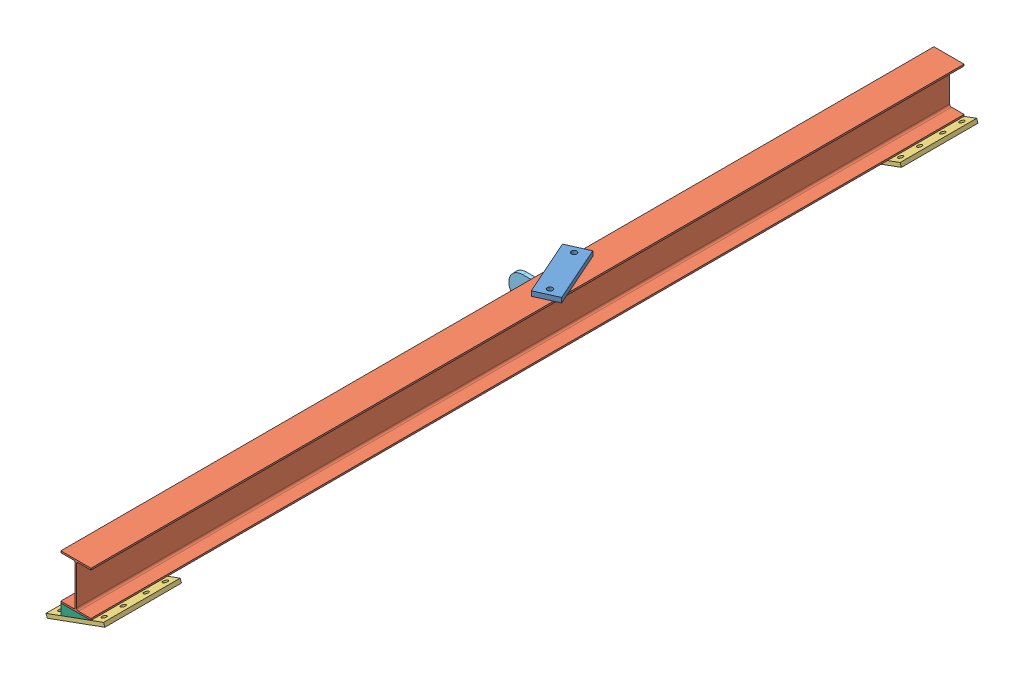
SolidWorks assembly _2014-10-29 WELMENT, STBD BOOM BASE, configuration Default. Lengths in mm.
Overall size (247.79 231.96 2895.6).
12 component instances, 7 part files, 24 mates.
Components (placement in the parent):
- PLATE, PILLOW BLOCK MOUNTING, BASE 1,2-1: PLATE, PILLOW BLOCK MOUNTING, BASE 1,2 [Default] at (-7.2804 74.93 -171.8129) x (0 1 0) z (-0.406737 0 -0.913545) size (15.88 76.2 203.2)
- BEAM, BASE 1-1: BEAM, BASE 1 [Default] at origin size (100.08 149.86 2895.6)
- PLATE, PLATFORM MOUNTING, BASE 1,2-1: PLATE, PLATFORM MOUNTING, BASE 1,2 [Default] at (-3.6654 -94.4765 -1320.8) x (0.34202 -0.939693 0) z (0 0 1) size (12.7 203.2 254)
- PLATE, PLATFORM MOUNTING, BASE 1,2-2: PLATE, PLATFORM MOUNTING, BASE 1,2 [Default] at (-3.6654 -94.4765 1320.8) x (0.34202 -0.939693 0) z (0 0 1) size (12.7 203.2 254)
- PLATE, BEAM REINFORCEMENT, BASE 1-1: PLATE, BEAM REINFORCEMENT, BASE 1 [Default] at (-46.863 0 0) size (6.35 138.94 1816.1)
- PADEYE, BEAM, BASE 1-1: PADEYE, BEAM, BASE 1 [Default] at (-50.038 0 -146.05) x (0 -0.069756 0.997564) z (0 -0.997564 -0.069756) size (12.7 101.6 101.6)
- FILLER PLATE 1-1: FILLER PLATE 1 [Default] at (50.038 -74.93 -1435.1) x (-1 0 0) z (0 -1 0) size (100.08 12.7 36.42)
- FILLER PLATE 1-2: FILLER PLATE 1 [Default] at (50.038 -74.93 -1193.8) x (-1 0 0) z (0 -1 0) size (100.08 12.7 36.42)
- FILLER PLATE 2-1: FILLER PLATE 2 [Default] at (-33.3992 -74.93 -1435.1) x (-1 0 0) z (0 0 -1) size (16.64 36.42 228.6)
- FILLER PLATE 2-2: FILLER PLATE 2 [Default] at (-33.3992 -74.93 1206.5) x (-1 0 0) z (0 0 -1) size (16.64 36.42 228.6)
- FILLER PLATE 1-3: FILLER PLATE 1 [Default] at (50.038 -74.93 1206.5) x (-1 0 0) z (0 -1 0) size (100.08 12.7 36.42)
- FILLER PLATE 1-4: FILLER PLATE 1 [Default] at (50.038 -74.93 1447.8) x (-1 0 0) z (0 -1 0) size (100.08 12.7 36.42)
Mates (geometry in assembly coordinates):
- Coincident1: coincident aligned: plane of BEAM, BASE 1-1 through (0 0 0) normal (0 0 1); plane of assembly through (0 0 0) normal (0 0 1)
- Coincident2: coincident aligned: plane of BEAM, BASE 1-1 through (0 0 0) normal (0 1 0); plane of assembly through (0 0 0) normal (0 1 0)
- Coincident3: coincident aligned: plane of BEAM, BASE 1-1 through (0 0 0) normal (1 0 0); plane of assembly through (0 0 0) normal (1 0 0)
- Coincident4: coincident anti-aligned: plane of BEAM, BASE 1-1 through (-50.038 74.93 1447.8) normal (0 1 0); plane of PLATE, PILLOW BLOCK MOUNTING, BASE 1,2-1 through (-7.2804 74.93 -171.8129) normal (0 -1 0)
- Angle2: planar angle = 0.418879 rad aligned: plane of PLATE, PILLOW BLOCK MOUNTING, BASE 1,2-1; plane of BEAM, BASE 1-1 through (0 0 0) normal (1 0 0)
- Distance1: distance = 1511.3 mm: point of PLATE, PILLOW BLOCK MOUNTING, BASE 1,2-1; line of BEAM, BASE 1-1 through (50.038 74.93 1447.8) axis (-1 0 0)
- Distance2: distance = 50.8 mm: line of BEAM, BASE 1-1 through (50.038 74.93 1447.8) axis (0 0 -1); point of PLATE, PILLOW BLOCK MOUNTING, BASE 1,2-1
- Coincident8: coincident: line of BEAM, BASE 1-1 through (50.038 -74.93 1447.8) axis (0 0 -1); plane of PLATE, PLATFORM MOUNTING, BASE 1,2-1 through (-3.6654 -94.4765 -1320.8) normal (-0.34202 0.939693 0)
- Angle3: planar angle = 0.349066 rad anti-aligned: plane of BEAM, BASE 1-1 through (50.038 -74.93 1447.8) normal (0 -1 0); plane of PLATE, PLATFORM MOUNTING, BASE 1,2-1 through (-3.6654 -94.4765 -1320.8) normal (-0.34202 0.939693 0)
- Distance3: distance = 44.45 mm: line of BEAM, BASE 1-1 through (50.038 -74.93 1447.8) axis (0 0 -1); line of PLATE, PLATFORM MOUNTING, BASE 1,2-1 through (91.8073 -59.7272 -1447.8) axis (0 0 1)
- Coincident11: coincident aligned: plane of BEAM, BASE 1-1 through (8.509 63.119 -1447.8) normal (0 0 -1); plane of PLATE, PLATFORM MOUNTING, BASE 1,2-1 through (96.151 -71.6613 -1447.8) normal (0 0 -1)
- Coincident12: coincident aligned: plane of BEAM, BASE 1-1 through (0 0 0) normal (0 1 0); plane of PLATE, BEAM REINFORCEMENT, BASE 1-1 through (-46.863 0 0) normal (0 1 0)
- Coincident14: coincident aligned: plane of BEAM, BASE 1-1 through (-50.038 69.469 1447.8) normal (-1 0 0); plane of PLATE, BEAM REINFORCEMENT, BASE 1-1 through (-50.038 0 0) normal (-1 0 0)
- Coincident15: coincident aligned: plane of BEAM, BASE 1-1 through (0 0 0) normal (0 0 1); plane of PLATE, BEAM REINFORCEMENT, BASE 1-1 through (-46.863 0 0) normal (0 0 1)
- Coincident16: coincident anti-aligned: plane of PLATE, BEAM REINFORCEMENT, BASE 1-1 through (-50.038 0 0) normal (-1 0 0); plane of PADEYE, BEAM, BASE 1-1 through (-50.038 -51.1192 -143.2591) normal (1 0 0)
- Angle4: planar angle = 0.069813 rad aligned: plane of BEAM, BASE 1-1 through (0 0 0) normal (0 0 1); plane of PADEYE, BEAM, BASE 1-1
- Distance4: distance = 1593.85 mm: line of PADEYE, BEAM, BASE 1-1 through (-156.718 0 -146.05) axis (1 0 0); plane of BEAM, BASE 1-1 through (8.509 63.119 1447.8) normal (0 0 1)
- Coincident19: coincident: plane of BEAM, BASE 1-1 through (0 0 0) normal (0 1 0); line of PADEYE, BEAM, BASE 1-1 through (-156.718 0 -146.05) axis (1 0 0)
- Coincident20: coincident anti-aligned: plane of PLATE, PLATFORM MOUNTING, BASE 1,2-1 through (-3.6654 -94.4765 -1320.8) normal (-0.34202 0.939693 0); plane of FILLER PLATE 1-1 through (-50.038 -111.3547 -1447.8) normal (0.34202 -0.939693 0)
- Coincident24: coincident aligned: plane of BEAM, BASE 1-1 through (8.509 63.119 -1447.8) normal (0 0 -1); plane of FILLER PLATE 1-1 through (50.038 -74.93 -1447.8) normal (0 0 -1)
- Coincident27: coincident anti-aligned: line of BEAM, BASE 1-1 through (50.038 -74.93 1447.8) axis (0 0 -1); line of FILLER PLATE 1-1 through (50.038 -74.93 -1447.8) axis (0 0 1)
- Coincident28: coincident anti-aligned: plane of BEAM, BASE 1-1 through (50.038 -74.93 1447.8) normal (0 -1 0); plane of FILLER PLATE 2-1 through (-33.3992 -74.93 -1206.5) normal (0 1 0)
- Coincident31: coincident anti-aligned: plane of FILLER PLATE 1-2 through (50.038 -74.93 -1206.5) normal (0 0 -1); plane of FILLER PLATE 2-1 through (-33.3992 -74.93 -1206.5) normal (0 0 1)
- Coincident34: coincident aligned: line of BEAM, BASE 1-1 through (-50.038 -74.93 1447.8) axis (0 0 -1); line of FILLER PLATE 2-1 through (-50.038 -74.93 -1206.5) axis (0 0 -1)
